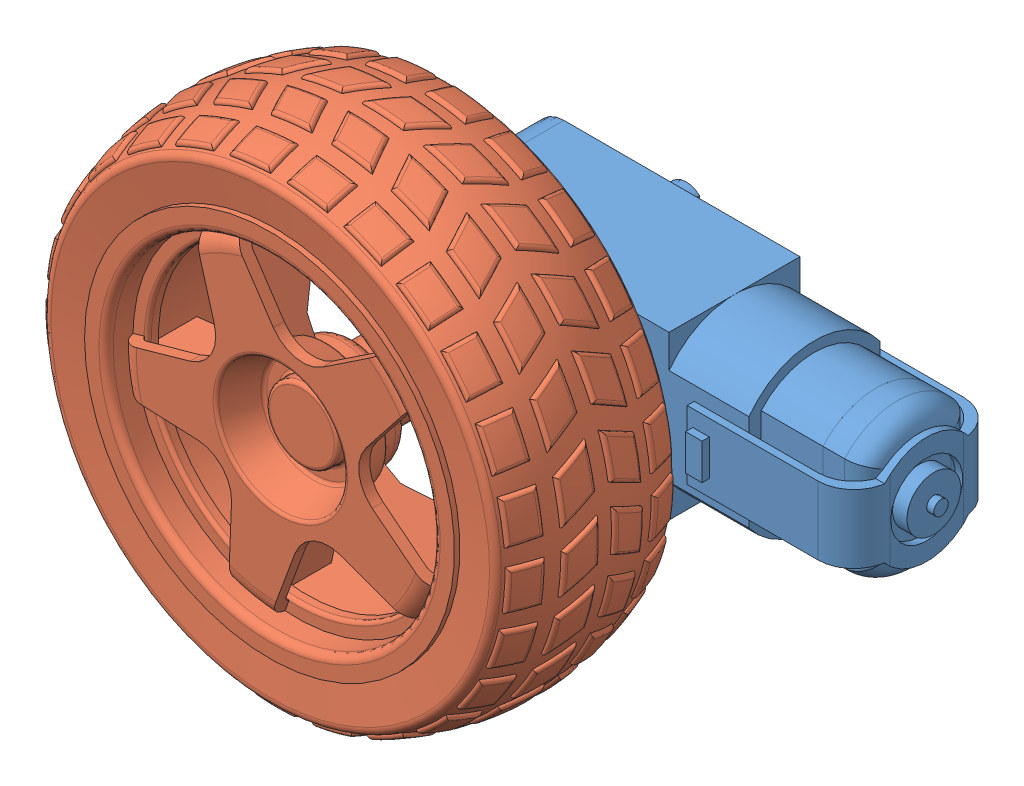
SolidWorks assembly Power Wheel, configuration Default. Lengths in mm.
Overall size (99.98 91.54 57.9).
2 component instances, 2 part files, 3 mates.
Components (placement in the parent):
- Motor Gear Box-1: Motor Gear Box [Default] at origin size (70.5 22.6 37.6)
- Wheel-1: Wheel [Default] at (11.3 11.3 30) x (0.908321 0.418275 0) z (0 0 1) size (68.99 69.02 30)
Mates (geometry in assembly coordinates):
- Coincident1: coordinate: point of Motor Gear Box-1
- Concentric1: concentric: cylinder of Motor Gear Box-1 through (11.3 11.3 9.7) axis (0 0 -1) radius 2.7; cylinder of Wheel-1 through (11.3 11.3 52.6127) axis (0 0 1) radius 4.9
- Coincident2: coincident anti-aligned: plane of Motor Gear Box-1 through (36.8 0 0) normal (0 0 1); plane of Wheel-1 through (11.3 11.3 0) normal (0 0 -1)
